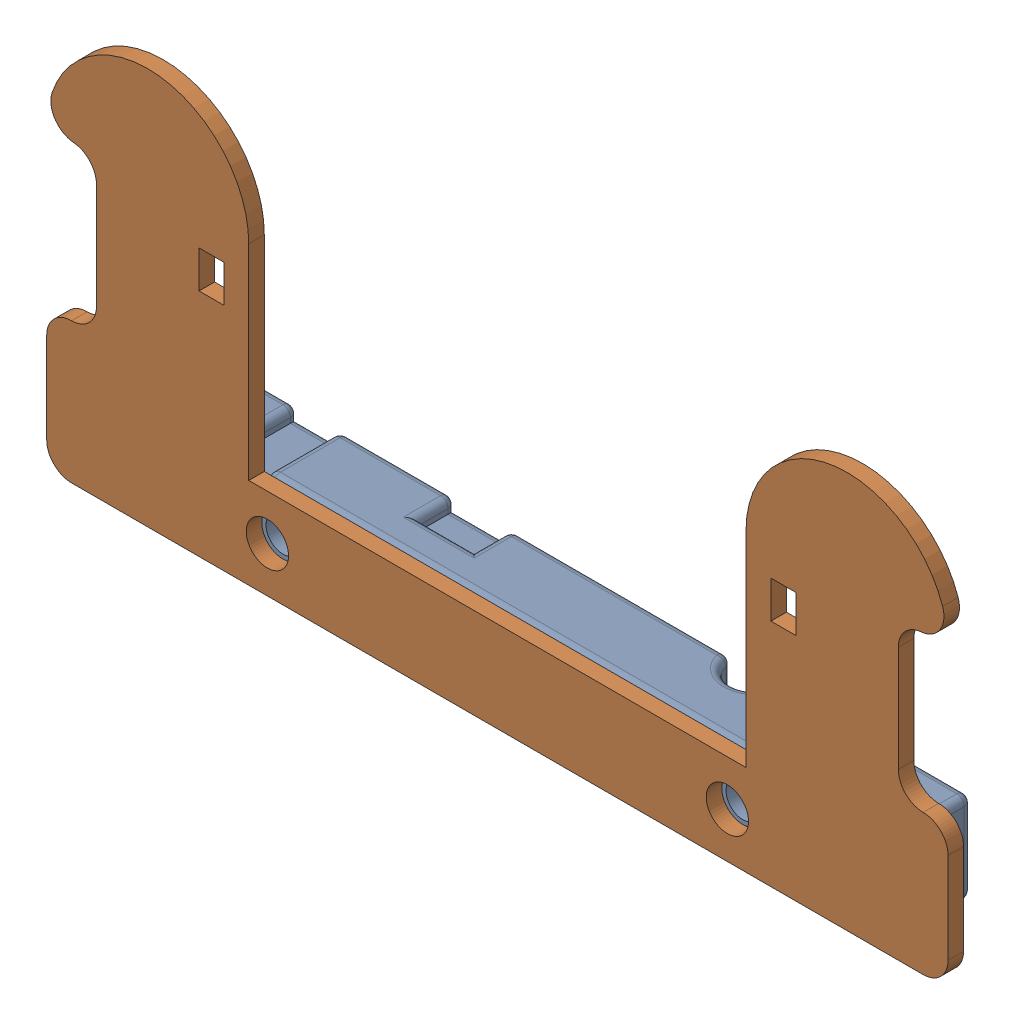
SolidWorks assembly wiring catch, configuration Default. Lengths in mm.
Overall size (92.07 40.54 9.21).
2 component instances, 2 part files, 7 mates.
Components (placement in the parent):
- wiringcatch_support-1: wiringcatch_support [Default] at origin size (78.49 9.27 7.62)
- wiringcatch_plate-1: wiringcatch_plate [Default] at (-6.7945 0 0) size (92.08 40.54 1.59)
Mates (geometry in assembly coordinates):
- Coincident1: coincident: plane of wiringcatch_support-1 through (0 9.271 0) normal (0 0 1); plane of wiringcatch_plate-1 through (3.5242 30.226 0) normal (0 0 -1)
- Concentric1: concentric: cylinder of wiringcatch_support-1 through (62.738 4.6355 -12.5053) axis (0 0 1) radius 1.7272; cylinder of wiringcatch_plate-1 through (62.738 4.6355 1.5875) axis (0 0 -1) radius 2.159
- Concentric2: concentric: cylinder of wiringcatch_support-1 through (15.748 4.6355 -12.5053) axis (0 0 1) radius 1.7272; cylinder of wiringcatch_plate-1 through (15.748 4.6355 1.5875) axis (0 0 -1) radius 2.159
- Concentric5: concentric: cylinder of wiringcatch_plate-1 through (4.318 38.1 1.5875) axis (0 0 -1) radius 3.81; cylinder of ? through (4.318 38.1 7.62) axis (0 0 -1) radius 3.175
- Concentric6: concentric: cylinder of wiringcatch_plate-1 through (74.168 38.1 1.5875) axis (0 0 -1) radius 3.81; cylinder of ? through (74.168 38.1 7.62) axis (0 0 -1) radius 3.175
- Coincident4: coincident: plane of wiringcatch_plate-1 through (3.5242 30.226 0) normal (0 0 -1); plane of ? through (74.168 38.1 0) normal (0 0 1)
- Coincident5: coincident: plane of wiringcatch_plate-1 through (3.5242 30.226 0) normal (0 0 -1); plane of ? through (4.318 38.1 0) normal (0 0 1)
